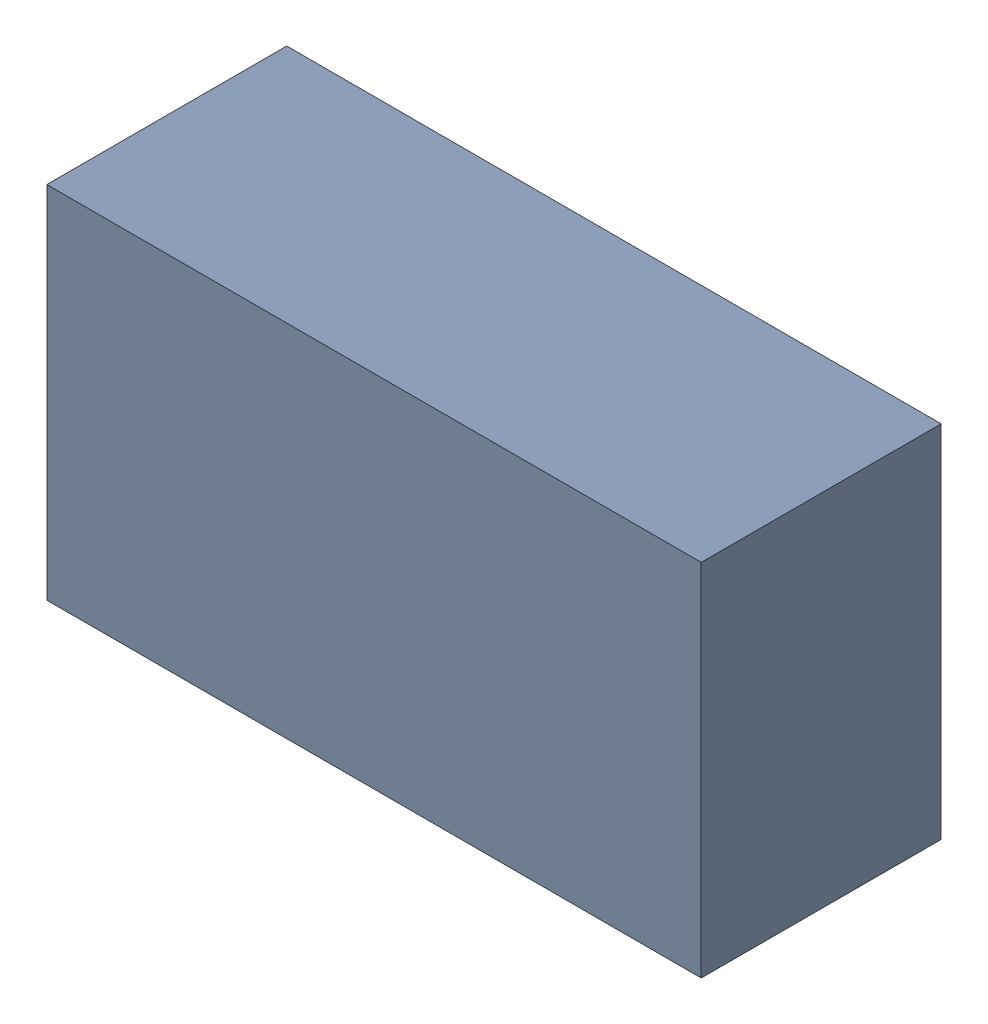
SolidWorks assembly U407PCB, configuration Default. Lengths in mm.
Overall size (3 1.65 1.1).
2 component instances, 1 part files, 0 mates.
Components (placement in the parent):
- 846483968-1: 846483968 [Default] at (136.9 104.4 -2.7638) size (3 1.65 1.1)
  - Extruded_7-1: Extruded_7 [Default] at origin size (3 1.65 1.1)
